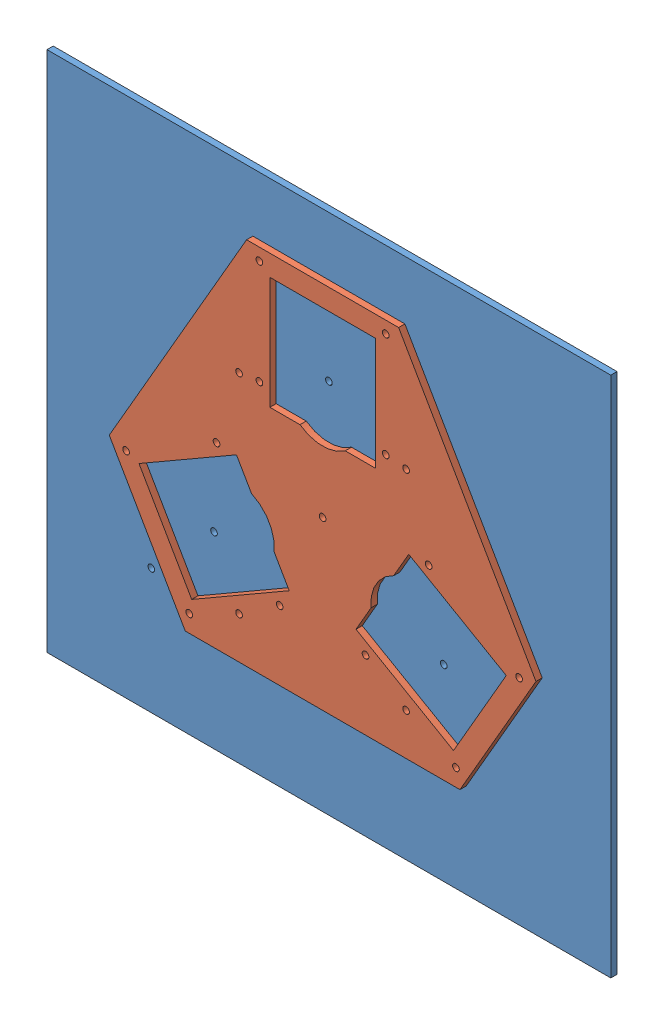
SolidWorks assembly 土台_ワイヤ放電, configuration ﾃﾞﾌｫﾙﾄ. Lengths in mm.
Overall size (270 250 6).
2 component instances, 2 part files, 3 mates.
Components (placement in the parent):
- 土台切り出し用板-1: 土台切り出し用板 [ﾃﾞﾌｫﾙﾄ] at (78.3713 161.9796 200.5338) size (270 250 3)
- 土台1段目板-1: 土台1段目板 [ﾃﾞﾌｫﾙﾄ] at (78.3713 161.9796 203.5338) size (204.33 176.96 3)
Mates (geometry in assembly coordinates):
- 一致1: coincident: plane of 土台切り出し用板-1 through (78.3713 161.9796 203.5338) normal (0 0 1); plane of 土台1段目板-1 through (78.3713 161.9796 203.5338) normal (0 0 -1)
- 平行1: parallel: plane of 土台切り出し用板-1 through (-56.6287 36.9796 203.5338) normal (0 -1 0); plane of 土台1段目板-1 through (78.3713 81.9796 206.5338) normal (0 -1 0)
- 同心円2: concentric: circle of 土台切り出し用板-1; circle of 土台1段目板-1
